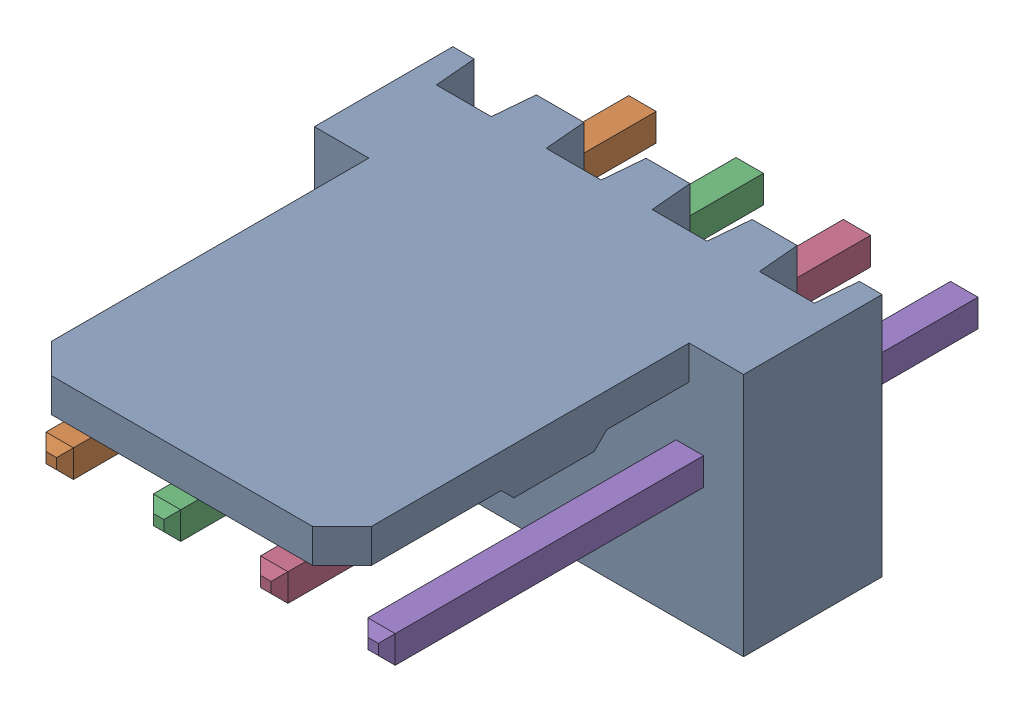
SolidWorks assembly Molex PCB 4 pin v3_6, configuration Default. Lengths in mm.
Overall size (10.16 5.79 14.92).
5 component instances, 2 part files, 0 mates.
Components (placement in the parent):
- BASE9710016-1: BASE9710016 [Default] at (2.54 2.895 -8.22) size (10.16 5.79 11.5)
- PINO9710016-1: PINO9710016 [Default] at (1.27 3.325 -0.72) size (0.65 0.65 14.2)
- PINO9710016-2: PINO9710016 [Default] at (3.81 3.325 -0.72) size (0.65 0.65 14.2)
- PINO9710016-3: PINO9710016 [Default] at (6.35 3.325 -0.72) size (0.65 0.65 14.2)
- PINO9710016-4: PINO9710016 [Default] at (8.89 3.325 -0.72) size (0.65 0.65 14.2)
